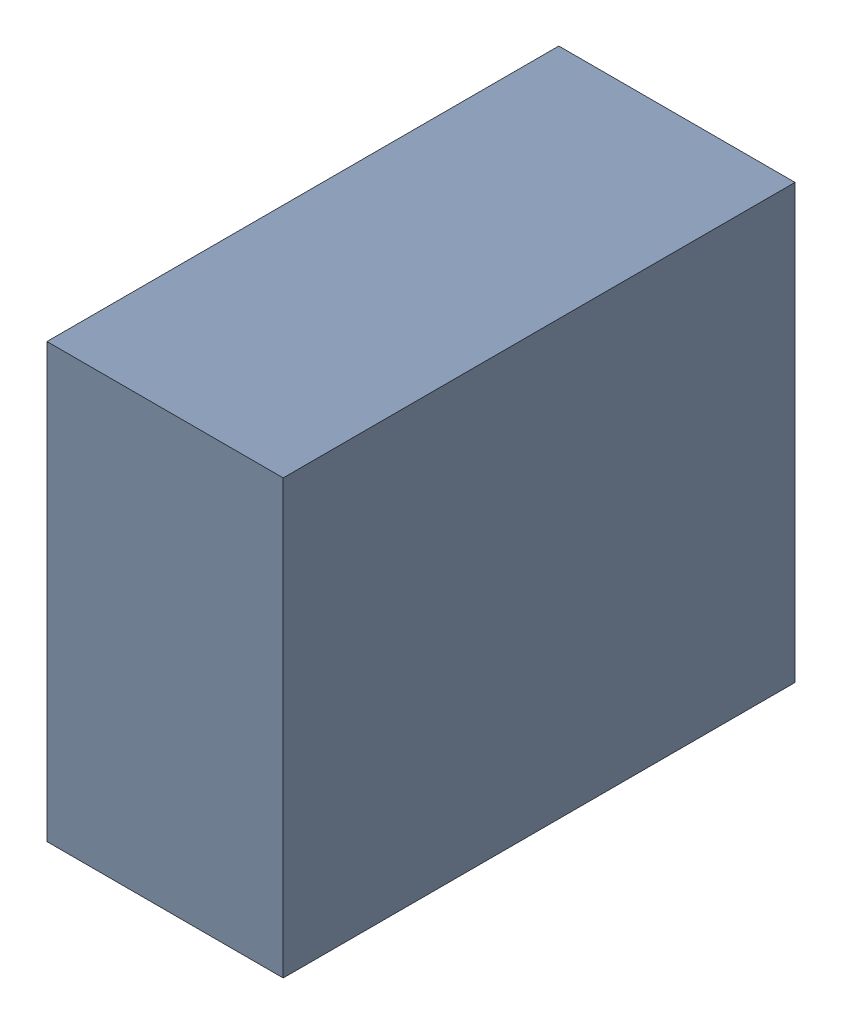
SolidWorks assembly C200, configuration Standard. Lengths in mm.
Overall size (0.6 1.1 1.3).
2 component instances, 1 part files, 0 mates.
Components (placement in the parent):
- 885542376-1: 885542376 [Standard] at (7.55 -11.75 0) size (0.6 1.1 1.3)
  - Extruded_25-1: Extruded_25 [Standard] at origin size (0.6 1.1 1.3)
